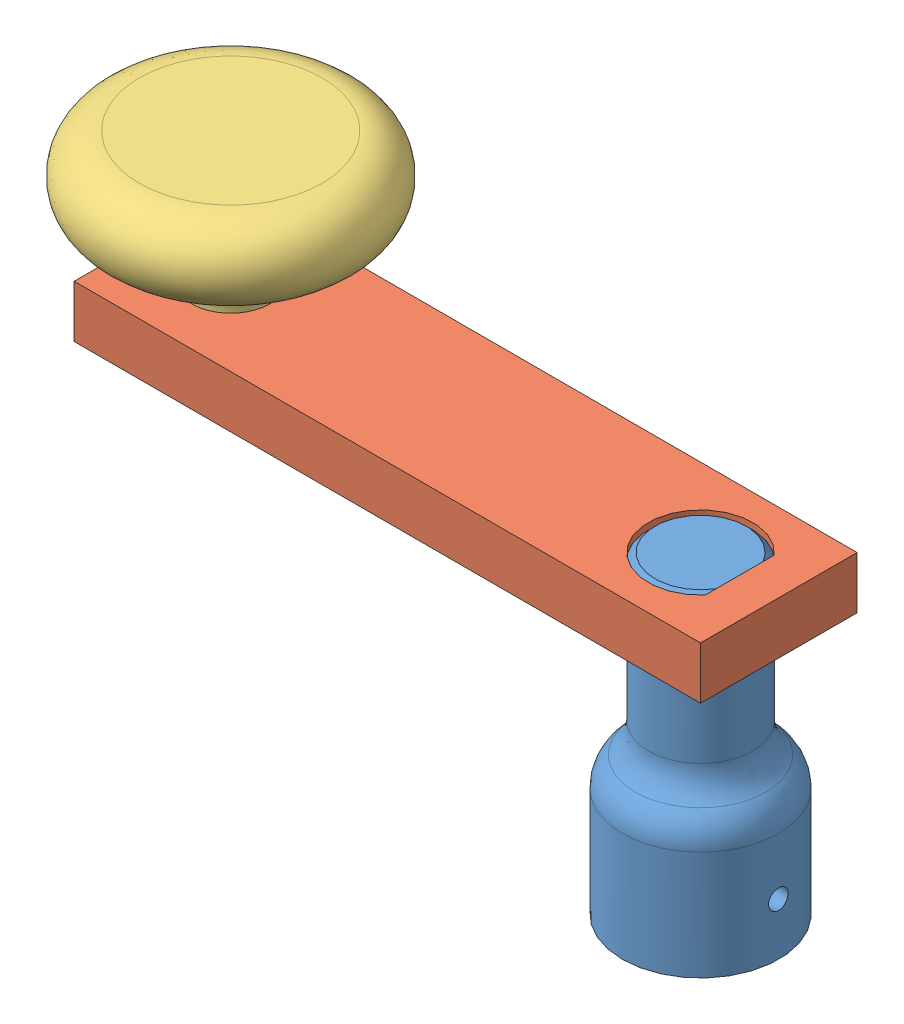
SolidWorks assembly crank-assy, configuration Default. Lengths in mm.
Overall size (82.55 53.98 31.75).
3 component instances, 3 part files, 8 mates.
Components (placement in the parent):
- crank-shaft-1: crank-shaft [Default] at origin size (19.05 38.1 19.05)
- crank-arm-1: crank-arm [Default] at (-66.675 31.75 -9.525) size (76.2 6.35 19.05)
- crank-knob-1: crank-knob [Default] at (-57.15 31.75 0) size (31.75 22.23 31.75)
Mates (geometry in assembly coordinates):
- MateCoincident1: coincident aligned: plane of crank-shaft-1; plane of assembly
- MateCoincident2: coincident aligned: plane of crank-shaft-1; plane of assembly
- MateCoincident3: coincident aligned: plane of crank-shaft-1; plane of assembly
- MateCoincident4: coincident aligned: plane of crank-shaft-1; plane of crank-arm-1
- MateCoincident5: coincident anti-aligned: plane of crank-shaft-1; plane of crank-arm-1
- MateConcentric1: concentric anti-aligned: cylinder of crank-shaft-1; cylinder of crank-arm-1
- MateCoincident6: coincident anti-aligned: plane of crank-arm-1; plane of crank-knob-1
- MateConcentric2: concentric anti-aligned: cylinder of crank-arm-1; cylinder of crank-knob-1
